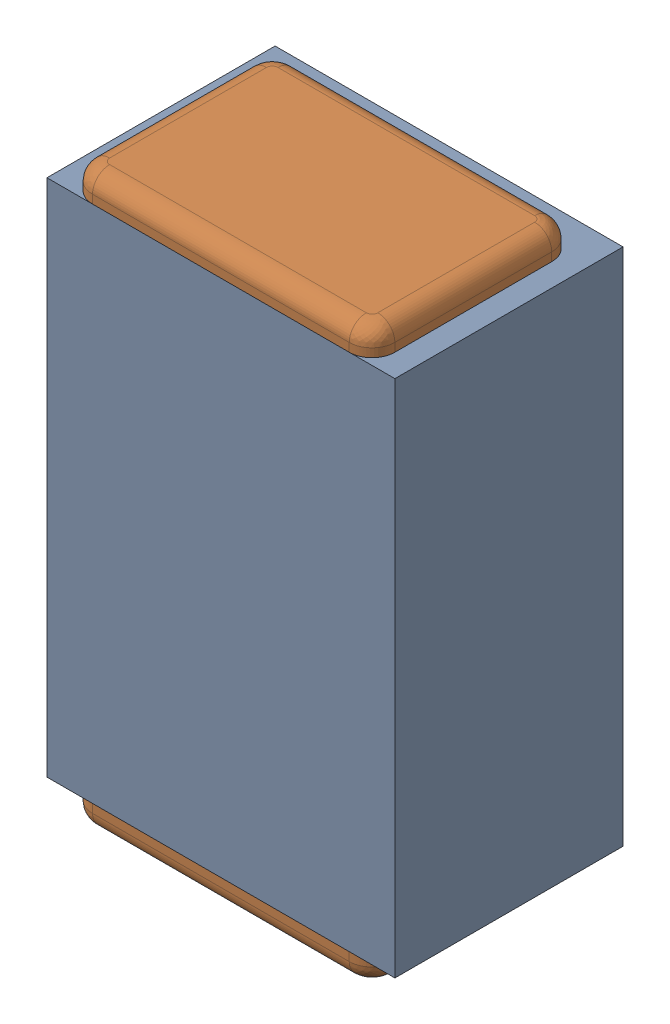
SolidWorks assembly C36, configuration Default. Lengths in mm.
Overall size (0.61 1 0.4).
3 component instances, 2 part files, 0 mates.
Components (placement in the parent):
- 1088881848-1: 1088881848 [Default] at (11.55 28.875 -2.044) size (0.61 0.91 0.4)
  - Extruded-1-1: Extruded-1 [Default] at origin size (0.61 0.91 0.4)
- C0402-1: C0402 [Default] at (11.5499 28.8749 -1.644) x (0 -1 0) z (1 0 0) size (1 0.36 0.54)
